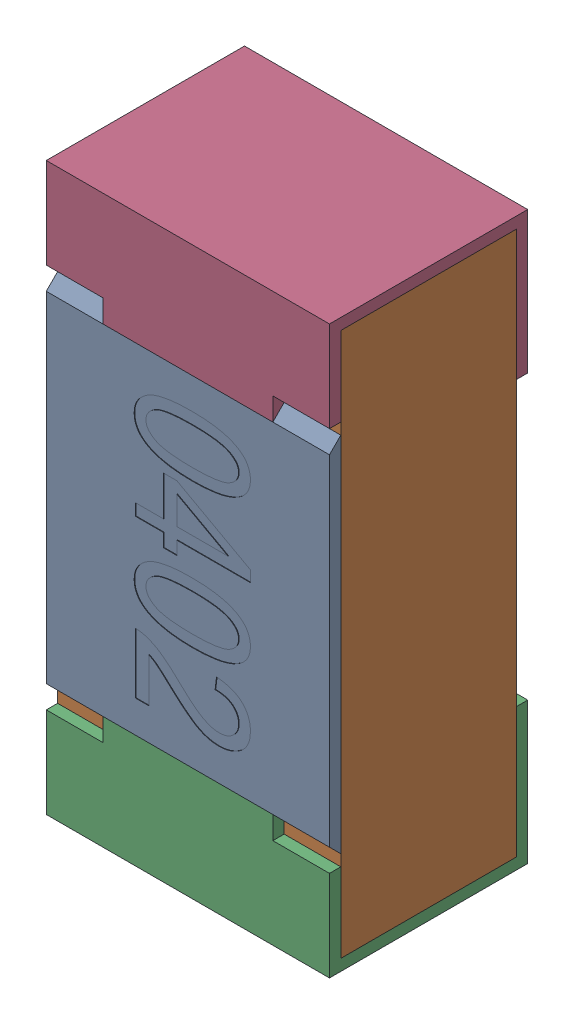
SolidWorks assembly R17, configuration Standard. Lengths in mm.
Overall size (0.5 1 0.35).
5 component instances, 4 part files, 0 mates.
Components (placement in the parent):
- R17-subassembly-1-1: R17-subassembly-1 [Standard] at (-15.6 -8.5001 0) x (0 -1 0) z (0 0 1) size (1 0.5 0.35)
  - User Library-R_0402-1: User Library-R_0402 [Standard] at origin size (0.64 0.5 0.02)
  - User Library-R_0402-1-1: User Library-R_0402-1 [Standard] at origin size (0.96 0.5 0.31)
  - User Library-R_0402-2-1: User Library-R_0402-2 [Standard] at origin size (0.25 0.5 0.35)
  - User Library-R_0402-3-1: User Library-R_0402-3 [Standard] at origin size (0.25 0.5 0.35)
